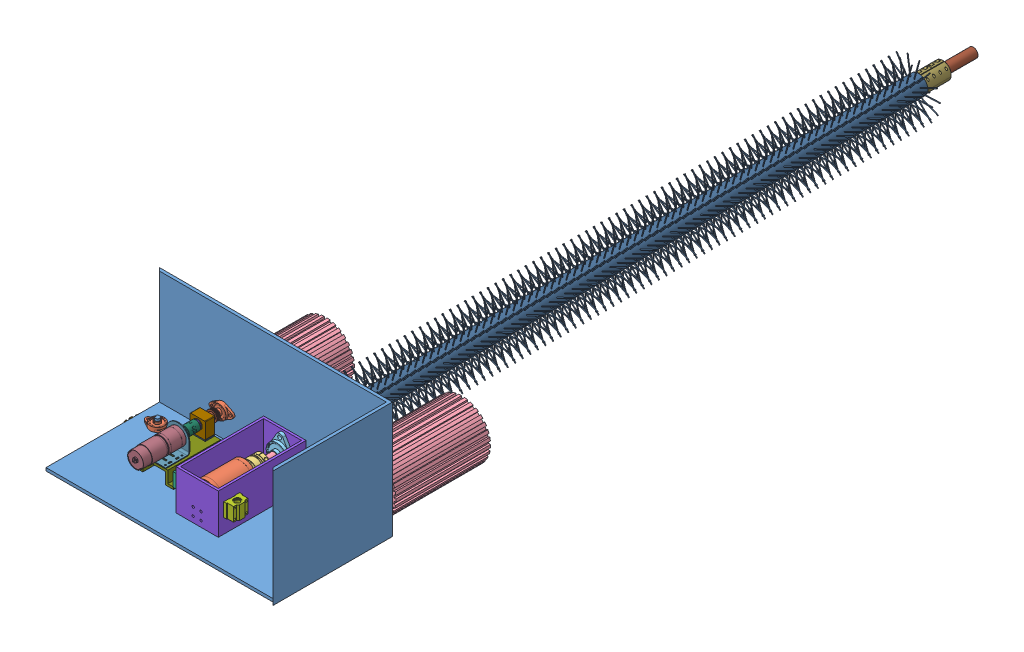
SolidWorks assembly moter in box assemly with 100mm supporting wheels - Copy, configuration Default. Lengths in mm.
Overall size (678.85 418 2128.3).
103 component instances, 31 part files, 10 mates.
Components (placement in the parent):
- box-1: box [Default] at (214.7869 209.4239 556.9442) size (616 308 316)
- wheel without moter subassembley-1: wheel without moter subassembley [Default] at (384.8983 36.9 0) size (173.81 173.65 354)
  - KFL001 block flange ball bearing 12 diameter shaft-1: KFL001 block flange ball bearing 12 diameter shaft [Default] at (58.0648 247.4239 406.9442) x (-0.381567 0.924341 0) z (0.924341 0.381567 0) size (38 16 63)
  - wheel shaft-1: wheel shaft [Default] at (58.0648 247.4239 234.5442) x (0.174278 -0.984697 0) z (-0.984697 -0.174278 0) size (12 354 12)
  - wheel rubber-1: wheel rubber [Default] at (58.0648 247.4239 134.5442) x (-0.174278 0.984697 0) z (0.984697 0.174278 0) size (149.8 250 150)
  - wheel rim-1: wheel rim [Default] at (58.0648 247.4239 134.5442) x (-0.174278 0.984697 0) z (0.984697 0.174278 0) size (130 250 130)
  - Bearing House v1.step-1: Bearing House v1.step [Default] at (58.0648 227.9239 462.9398) x (-1 0 0) z (0 1 0) size (40 25 45.94)
    - SKF_61901-2Z.step-1: SKF_61901-2Z.step [Default] at (0 -8 19.5) x (0 -1 0) z (0 0 1) size (6 24 24)
      - SKF_61901-2Z_ball1.step-1: SKF_61901-2Z_ball1.step [Default] at (6 16.2812 -5.2901) x (-1 0 0) z (0 0 1) size (3.18 3.17 3.17)
      - SKF_61901-2Z_ball1.step-2: SKF_61901-2Z_ball1.step [Default] at (6 11.7812 -8.5595) x (-1 0 0) z (0 0 1) size (3.18 3.17 3.17)
      - SKF_61901-2Z_ball1.step-3: SKF_61901-2Z_ball1.step [Default] at (6 6.2188 -8.5595) x (-1 0 0) z (0 0 1) size (3.18 3.17 3.17)
      - SKF_61901-2Z_ball1.step-4: SKF_61901-2Z_ball1.step [Default] at (6 1.7188 -5.2901) x (-1 0 0) z (0 0 1) size (3.18 3.17 3.17)
      - SKF_61901-2Z_ball1.step-5: SKF_61901-2Z_ball1.step [Default] at (6 0 0) x (-1 0 0) z (0 0 1) size (3.18 3.17 3.17)
      - SKF_61901-2Z_ball1.step-6: SKF_61901-2Z_ball1.step [Default] at (6 1.7188 5.2901) x (-1 0 0) z (0 0 1) size (3.18 3.17 3.17)
      - SKF_61901-2Z_ball1.step-7: SKF_61901-2Z_ball1.step [Default] at (6 6.2188 8.5595) x (-1 0 0) z (0 0 1) size (3.18 3.17 3.17)
      - SKF_61901-2Z_ball1.step-8: SKF_61901-2Z_ball1.step [Default] at (6 11.7812 8.5595) x (-1 0 0) z (0 0 1) size (3.18 3.17 3.17)
      - SKF_61901-2Z_ball1.step-9: SKF_61901-2Z_ball1.step [Default] at (6 16.2812 5.2901) x (-1 0 0) z (0 0 1) size (3.18 3.17 3.17)
      - SKF_61901-2Z_ball1.step-10: SKF_61901-2Z_ball1.step [Default] at (6 18 0) x (-1 0 0) z (0 0 1) size (3.18 3.17 3.17)
      - SKF_61901-2Z_or.step-1: SKF_61901-2Z_or.step [Default] x (1 0 0) z (0 0 -1) size (6 24 24)
      - SKF_61901-2Z_ir.step-1: SKF_61901-2Z_ir.step [Default] x (1 0 0) z (0 0 -1) size (6 21.4 21.4)
    - SKF_61901-2Z.step-2: SKF_61901-2Z.step [Default] at (0 5 19.5) x (0 1 0) z (0 0 1) size (6 24 24)
      - SKF_61901-2Z_ball1.step-1: SKF_61901-2Z_ball1.step [Default] at (6 16.2812 -5.2901) x (-1 0 0) z (0 0 1) size (3.18 3.17 3.17)
      - SKF_61901-2Z_ball1.step-2: SKF_61901-2Z_ball1.step [Default] at (6 11.7812 -8.5595) x (-1 0 0) z (0 0 1) size (3.18 3.17 3.17)
      - SKF_61901-2Z_ball1.step-3: SKF_61901-2Z_ball1.step [Default] at (6 6.2188 -8.5595) x (-1 0 0) z (0 0 1) size (3.18 3.17 3.17)
      - SKF_61901-2Z_ball1.step-4: SKF_61901-2Z_ball1.step [Default] at (6 1.7188 -5.2901) x (-1 0 0) z (0 0 1) size (3.18 3.17 3.17)
      - SKF_61901-2Z_ball1.step-5: SKF_61901-2Z_ball1.step [Default] at (6 0 0) x (-1 0 0) z (0 0 1) size (3.18 3.17 3.17)
      - SKF_61901-2Z_ball1.step-6: SKF_61901-2Z_ball1.step [Default] at (6 1.7188 5.2901) x (-1 0 0) z (0 0 1) size (3.18 3.17 3.17)
      - SKF_61901-2Z_ball1.step-7: SKF_61901-2Z_ball1.step [Default] at (6 6.2188 8.5595) x (-1 0 0) z (0 0 1) size (3.18 3.17 3.17)
      - SKF_61901-2Z_ball1.step-8: SKF_61901-2Z_ball1.step [Default] at (6 11.7812 8.5595) x (-1 0 0) z (0 0 1) size (3.18 3.17 3.17)
      - SKF_61901-2Z_ball1.step-9: SKF_61901-2Z_ball1.step [Default] at (6 16.2812 5.2901) x (-1 0 0) z (0 0 1) size (3.18 3.17 3.17)
      - SKF_61901-2Z_ball1.step-10: SKF_61901-2Z_ball1.step [Default] at (6 18 0) x (-1 0 0) z (0 0 1) size (3.18 3.17 3.17)
      - SKF_61901-2Z_or.step-1: SKF_61901-2Z_or.step [Default] x (1 0 0) z (0 0 -1) size (6 24 24)
      - SKF_61901-2Z_ir.step-1: SKF_61901-2Z_ir.step [Default] x (1 0 0) z (0 0 -1) size (6 21.4 21.4)
    - Universal Bearing Housing.step-1: Universal Bearing Housing.step [Default] at (0 11.0044 14.0358) x (1 0 0) z (0 -1 0) size (40 43 25)
    - Universal Bearing Housing Spacer.step-1: Universal Bearing Housing Spacer.step [Default] at (0 -1.5 -7.4) x (1 0 0) z (0 1 0) size (40 3 25)
  - GT2 40T id 12mm bw 7mm-1: GT2 40T id 12mm bw 7mm [Výchozí] at (58.0648 247.4239 435.4442) x (0.924379 0.381477 0) z (0.381477 -0.924379 0) size (28.2 17 28.2)
  - height extender 25mm-1: height extender 25mm [Default] at (7.0648 186.5239 448.9398) size (102 37 25)
- Wheel with moter assembly-1: Wheel with moter assembly [Default] at (12.7256 37 0) size (163.26 163.44 510.81)
  - Motor DC PG45-1: Motor DC PG45 [Default] at (70.1664 247.4239 638.3442) x (0.707107 0.707107 0) z (-0.707107 0.707107 0) size (45 146.01 45)
  - Mounting Bracket Motor DC PG45 Orange-1: Mounting Bracket Motor DC PG45 Orange [Default] at (91.7552 243.9192 526.8442) x (-1 0 0) z (0 0 -1) size (60 60 63.93)
  - KFL001 block flange ball bearing 12 diameter shaft-1: KFL001 block flange ball bearing 12 diameter shaft [Default] at (70.1664 247.4239 406.9442) x (-0.034258 0.999413 0) z (0.999413 0.034258 0) size (38 16 63)
  - wheel shaft-1: wheel shaft [Default] at (70.1664 247.4239 234.5442) x (0.995554 -0.094191 0) z (-0.094191 -0.995554 0) size (12 354 12)
  - Shaft_Coupler_6.35x12mm-1: Shaft_Coupler_6.35x12mm [По умолчанию] at (70.1664 247.4239 508.9442) x (0.647293 0.762241 0) z (-0.762241 0.647293 0) size (25.41 30 25.41)
  - wheel rubber-1: wheel rubber [Default] at (70.1664 247.4239 134.5442) x (-0.995554 0.094191 0) z (0.094191 0.995554 0) size (149.8 250 150)
  - wheel rim-1: wheel rim [Default] at (70.1664 247.4239 134.5442) x (-0.995554 0.094191 0) z (0.094191 0.995554 0) size (130 250 130)
  - Bearing House v1.step-1: Bearing House v1.step [Default] at (70.1664 227.9239 462.9398) x (-1 0 0) z (0 1 0) size (40 25 45.94)
    - SKF_61901-2Z.step-1: SKF_61901-2Z.step [Default] at (0 -8 19.5) x (0 -1 0) z (0 0 1) size (6 24 24)
      - SKF_61901-2Z_ball1.step-1: SKF_61901-2Z_ball1.step [Default] at (6 16.2812 -5.2901) x (-1 0 0) z (0 0 1) size (3.18 3.17 3.17)
      - SKF_61901-2Z_ball1.step-2: SKF_61901-2Z_ball1.step [Default] at (6 11.7812 -8.5595) x (-1 0 0) z (0 0 1) size (3.18 3.17 3.17)
      - SKF_61901-2Z_ball1.step-3: SKF_61901-2Z_ball1.step [Default] at (6 6.2188 -8.5595) x (-1 0 0) z (0 0 1) size (3.18 3.17 3.17)
      - SKF_61901-2Z_ball1.step-4: SKF_61901-2Z_ball1.step [Default] at (6 1.7188 -5.2901) x (-1 0 0) z (0 0 1) size (3.18 3.17 3.17)
      - SKF_61901-2Z_ball1.step-5: SKF_61901-2Z_ball1.step [Default] at (6 0 0) x (-1 0 0) z (0 0 1) size (3.18 3.17 3.17)
      - SKF_61901-2Z_ball1.step-6: SKF_61901-2Z_ball1.step [Default] at (6 1.7188 5.2901) x (-1 0 0) z (0 0 1) size (3.18 3.17 3.17)
      - SKF_61901-2Z_ball1.step-7: SKF_61901-2Z_ball1.step [Default] at (6 6.2188 8.5595) x (-1 0 0) z (0 0 1) size (3.18 3.17 3.17)
      - SKF_61901-2Z_ball1.step-8: SKF_61901-2Z_ball1.step [Default] at (6 11.7812 8.5595) x (-1 0 0) z (0 0 1) size (3.18 3.17 3.17)
      - SKF_61901-2Z_ball1.step-9: SKF_61901-2Z_ball1.step [Default] at (6 16.2812 5.2901) x (-1 0 0) z (0 0 1) size (3.18 3.17 3.17)
      - SKF_61901-2Z_ball1.step-10: SKF_61901-2Z_ball1.step [Default] at (6 18 0) x (-1 0 0) z (0 0 1) size (3.18 3.17 3.17)
      - SKF_61901-2Z_or.step-1: SKF_61901-2Z_or.step [Default] x (1 0 0) z (0 0 -1) size (6 24 24)
      - SKF_61901-2Z_ir.step-1: SKF_61901-2Z_ir.step [Default] x (1 0 0) z (0 0 -1) size (6 21.4 21.4)
    - SKF_61901-2Z.step-2: SKF_61901-2Z.step [Default] at (0 5 19.5) x (0 1 0) z (0 0 1) size (6 24 24)
      - SKF_61901-2Z_ball1.step-1: SKF_61901-2Z_ball1.step [Default] at (6 16.2812 -5.2901) x (-1 0 0) z (0 0 1) size (3.18 3.17 3.17)
      - SKF_61901-2Z_ball1.step-2: SKF_61901-2Z_ball1.step [Default] at (6 11.7812 -8.5595) x (-1 0 0) z (0 0 1) size (3.18 3.17 3.17)
      - SKF_61901-2Z_ball1.step-3: SKF_61901-2Z_ball1.step [Default] at (6 6.2188 -8.5595) x (-1 0 0) z (0 0 1) size (3.18 3.17 3.17)
      - SKF_61901-2Z_ball1.step-4: SKF_61901-2Z_ball1.step [Default] at (6 1.7188 -5.2901) x (-1 0 0) z (0 0 1) size (3.18 3.17 3.17)
      - SKF_61901-2Z_ball1.step-5: SKF_61901-2Z_ball1.step [Default] at (6 0 0) x (-1 0 0) z (0 0 1) size (3.18 3.17 3.17)
      - SKF_61901-2Z_ball1.step-6: SKF_61901-2Z_ball1.step [Default] at (6 1.7188 5.2901) x (-1 0 0) z (0 0 1) size (3.18 3.17 3.17)
      - SKF_61901-2Z_ball1.step-7: SKF_61901-2Z_ball1.step [Default] at (6 6.2188 8.5595) x (-1 0 0) z (0 0 1) size (3.18 3.17 3.17)
      - SKF_61901-2Z_ball1.step-8: SKF_61901-2Z_ball1.step [Default] at (6 11.7812 8.5595) x (-1 0 0) z (0 0 1) size (3.18 3.17 3.17)
      - SKF_61901-2Z_ball1.step-9: SKF_61901-2Z_ball1.step [Default] at (6 16.2812 5.2901) x (-1 0 0) z (0 0 1) size (3.18 3.17 3.17)
      - SKF_61901-2Z_ball1.step-10: SKF_61901-2Z_ball1.step [Default] at (6 18 0) x (-1 0 0) z (0 0 1) size (3.18 3.17 3.17)
      - SKF_61901-2Z_or.step-1: SKF_61901-2Z_or.step [Default] x (1 0 0) z (0 0 -1) size (6 24 24)
      - SKF_61901-2Z_ir.step-1: SKF_61901-2Z_ir.step [Default] x (1 0 0) z (0 0 -1) size (6 21.4 21.4)
    - Universal Bearing Housing.step-1: Universal Bearing Housing.step [Default] at (0 11.0044 14.0358) x (1 0 0) z (0 -1 0) size (40 43 25)
    - Universal Bearing Housing Spacer.step-1: Universal Bearing Housing Spacer.step [Default] at (0 -1.5 -7.4) x (1 0 0) z (0 1 0) size (40 3 25)
  - GT2 40T id 12mm bw 7mm-1: GT2 40T id 12mm bw 7mm [Výchozí] at (70.1664 247.4239 435.4442) x (0.924379 0.381477 0) z (0.381477 -0.924379 0) size (28.2 17 28.2)
  - height extender 140mm-1: height extender 140mm [Default] at (19.1664 186.4239 448.9442) size (102 37 140)
- support wheel with block flange 100mm assembly-1: support wheel with block flange 100mm assembly [Default] at (-341.3848 337.3003 401.9413) x (0.243495 0 0.969902) z (0.969902 0 -0.243495) size (211.82 140 211.83)
  - side wheel (rubber+rim)-1: side wheel (rubber+rim) [Default] at (69.3134 97.8604 176.3592) size (211.82 100 211.83)
    - side wheel rim-1: side wheel rim [Default] at (68.1365 40.0161 108.3416) size (130 100 130)
    - side wheel rubber-1: side wheel rubber [Default] at (68.1365 40.0161 108.3416) x (0.734903 0 0.678172) z (-0.678172 0 0.734903) size (149.8 100 150)
  - support wheel shaft 100mm-1: support wheel shaft 100mm [Default] at (137.4499 201.8764 284.7008) x (1 0 0) z (0 0 -1) size (12 140 12)
  - KFL001 block flange ball bearing 12 diameter shaft-1: KFL001 block flange ball bearing 12 diameter shaft [Default] at (137.4499 119.8764 284.7008) x (-0.969898 0 0.243511) z (0.243511 0 0.969898) size (38 16 63)
- box_assemble v11-1: box_assemble v11 [Default] at (246.4099 223.4239 632.9442) x (-1 0 0) z (0 0 -1) size (171.55 172.21 2052.3)
  - box_assemble v11.step-1: box_assemble v11.step [Default] at origin size (168 106 256)
    - brush_motor_assembly.step-1: brush_motor_assembly.step [Default] at (0 -130 0) size (68.2 68.2 242)
      - my6812.step-1: my6812.step [Default] at (0 180 68.5) size (68.2 68.2 138.5)
      - SDCS-47C.step-1: SDCS-47C.step [Default] at (0 180 131.5) x (1 0 0) z (0 1 0) size (47 35.65 47)
      - axle_brush.step-1: axle_brush.step [Default] at (0 180 232) size (20 20 98)
    - KFL004 block flange ball bearing 20 diameter shaft.step-1: KFL004 block flange ball bearing 20 diameter shaft.step [Default] at (0 50 220) x (1 0 0) z (0 1 0) size (55 23 90)
    - Pillow Block Mk 1.step-1: Pillow Block Mk 1.step [Default] at (84 32.4199 211.75) x (0 0 -1) z (0 1 0) size (42 28 36)
    - Pillow Block Mk 1.step-2: Pillow Block Mk 1.step [Default] at (84 32.4199 50.25) x (0 0 -1) z (0 1 0) size (42 28 36)
    - Pillow Block Mk 1.step-3: Pillow Block Mk 1.step [Default] at origin size (42 28 36)
    - Pillow Block Mk 1 v1(Mirror).step-1: Pillow Block Mk 1 v1(Mirror).step [Default] at (-84 32.4199 211.75) x (0 0 -1) z (0 -1 0) size (42 28 36)
    - Pillow Block Mk 1 v1(Mirror).step-2: Pillow Block Mk 1 v1(Mirror).step [Default] at (-84 32.4199 50.25) x (0 0 -1) z (0 -1 0) size (42 28 36)
    - box_assemble.step-1: box_assemble.step [Default] at origin size (112 106 232)
    - box_assemble-0.step-1: box_assemble-0.step [Default] at origin size (10 10 20)
  - brush_coupling_assembly-1: brush_coupling_assembly [Default] at (1577.6534 -554.8547 2141.02) x (-0.167929 0.985799 0) z (-0.985799 -0.167929 0) size (149.39 1790 148.57)
    - Part2-1: Part2 [Default] at (861.1995 239.721 1453.6763) size (149.39 1560 148.57)
    - axle_brush v7-1: axle_brush v7 [Default] at (861.1995 204.722 1453.6763) x (-1 0 0) z (0 -1 0) size (25 28.24 110)
    - 5SM025025TK-StaffordManufacturingCorp.-3D-07-14-2023 (1).stp-1: 5SM025025TK-StaffordManufacturingCorp.-3D-07-14-2023 (1).stp [Default] at (861.1995 174.721 1453.6763) x (-1 0 0) z (0 0 -1) size (44.97 65 45)
    - 5SM025025TK-StaffordManufacturingCorp.-3D-07-14-2023 (1).stp-2: 5SM025025TK-StaffordManufacturingCorp.-3D-07-14-2023 (1).stp [Default] at (861.1995 1804.721 1453.6763) x (1 0 0) z (0 0 -1) size (44.97 65 45)
    - axle_brush v7-2: axle_brush v7 [Default] at (861.1995 1774.72 1453.6763) x (1 0 0) z (0 1 0) size (25 28.24 110)
  - SDCS-54C.step-1: SDCS-54C.step [Default] at (0 50 233) x (-0.975846 -0.21846 0) z (0.21846 -0.975846 0) size (54.01 42.32 54.01)
Mates (geometry in assembly coordinates):
- Parallel6: parallel anti-aligned: line of box-1 through (-85.2131 217.4239 406.9442) axis (0 0 1); line of wheel without moter subassembley-1/Bearing House v1.step-1/Universal Bearing Housing Spacer.step-1 through (422.9631 254.4239 472.9398) axis (0 0 -1)
- Parallel7: parallel anti-aligned: line of box-1 through (-85.2131 217.4239 706.9442) axis (1 0 0); line of wheel without moter subassembley-1/Bearing House v1.step-1/Universal Bearing Housing Spacer.step-1 through (461.9631 254.4239 473.9398) axis (-1 0 0)
- Coincident18: coincident anti-aligned: plane of box-1 through (214.7869 517.4239 406.9442) normal (0 0 1); plane of wheel without moter subassembley-1/KFL001 block flange ball bearing 12 diameter shaft-1 through (442.9631 284.3239 406.9442) normal (0 0 -1)
- Coincident22: coincident anti-aligned: plane of box-1 through (214.7869 217.4239 556.9442) normal (0 1 0); plane of wheel without moter subassembley-1/height extender 25mm-1 through (412.9631 217.4239 473.9398) normal (0 -1 0)
- Coincident23: coincident anti-aligned: plane of box-1 through (214.7869 217.4239 556.9442) normal (0 1 0); plane of Wheel with moter assembly-1/height extender 140mm-1 through (52.892 217.4239 588.9442) normal (0 -1 0)
- Coincident24: coincident anti-aligned: plane of box-1 through (214.7869 517.4239 406.9442) normal (0 0 1); plane of Wheel with moter assembly-1/KFL001 block flange ball bearing 12 diameter shaft-1 through (82.892 284.4239 406.9442) normal (0 0 -1)
- Coincident25: coincident anti-aligned: plane of box-1 through (214.7869 217.4239 556.9442) normal (0 1 0); plane of support wheel with block flange 100mm assembly-1/KFL001 block flange ball bearing 12 diameter shaft-1 through (-31.7846 217.4239 465.9312) normal (0 -1 0)
- Angle3: planar angle = 0.499688 rad aligned: line of support wheel with block flange 100mm assembly-1/KFL001 block flange ball bearing 12 diameter shaft-1 through (-22.6807 217.4239 482.6081) axis (0.877732 0 -0.479152); line of box-1 through (-85.2131 217.4239 406.9442) axis (1 0 0)
- Coincident26: coincident anti-aligned: plane of box-1 through (214.7869 217.4239 556.9442) normal (0 1 0); plane of box_assemble v11-1/box_assemble v11.step-1/box_assemble.step-1 through (246.4099 217.4239 522.9442) normal (0 -1 0)
- Coincident27: coincident anti-aligned: plane of box-1 through (214.7869 517.4239 406.9442) normal (0 0 1); plane of box_assemble v11-1/box_assemble v11.step-1/box_assemble.step-1 through (296.4099 223.4239 406.9442) normal (0 0 -1)
